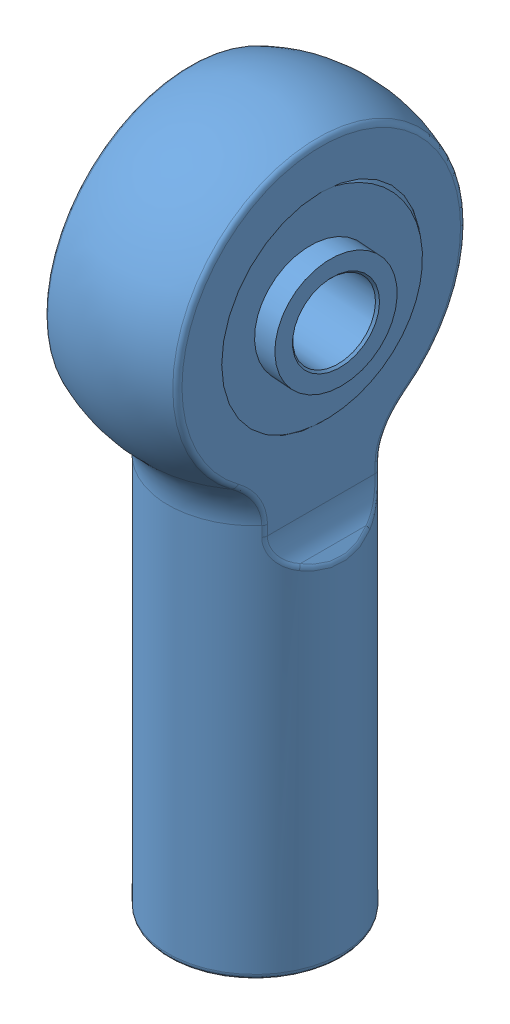
SolidWorks assembly REP3H5 Assy, configuration 1_START HERE. Lengths in mm.
Overall size (13.22 45.4 21.64).
2 component instances, 1 part files, 1 mates.
Components (placement in the parent):
- REP3H5-1: REP3H5 [Body] at origin size (11.11 44.84 19.84)
- REP3H5-2: REP3H5 [Ball] x (0.996662 0.01392 0.080447) z (-0.080726 0.020747 0.99652) size (11.11 44.84 19.84)
Mates (geometry in assembly coordinates):
- Concentric1: concentric: sphere of REP3H5-1; sphere of REP3H5-2
